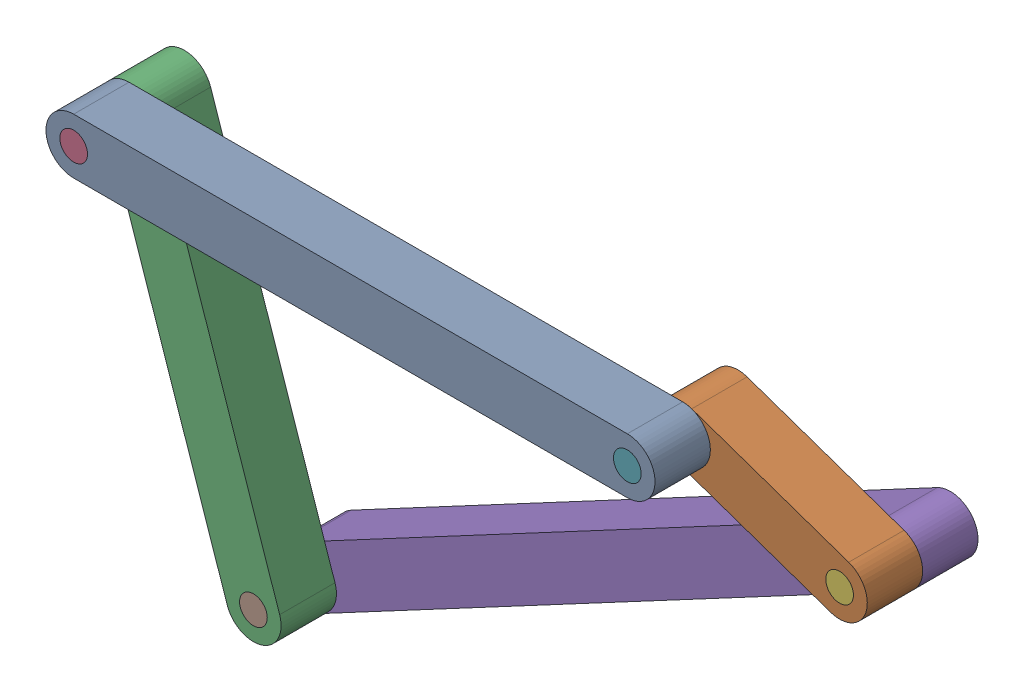
SolidWorks assembly 4 bar mech, configuration Default. Lengths in mm.
Overall size (141.45 79.42 30).
8 component instances, 5 part files, 21 mates.
Components (placement in the parent):
- 10-2: 10 [Default] at (20.648 20.834 -4.1693) size (110 10 10)
- 3-2: 3 [Default] at (84.8211 15.9225 -14.1693) x (-0.944872 0.327439 0) z (0 0 1) size (40 10 10)
- 7-2: 7 [Default] at (-18.1192 -12.3145 -14.1693) x (0.320937 -0.947101 0) z (0 0 1) size (80 10 10)
- Pin-2: Pin [Default] at (-29.352 20.834 -14.1693) x (-0.994228 -0.107291 0) z (0 0 1) size (5 5 20)
- 12-3: 12 [Default] at (46.0539 -17.2261 -24.1693) x (0.882338 0.470616 0) z (0 0 1) size (130 10 10)
- Pin-3: Pin [Default] at (98.9942 11.0109 -24.1693) size (5 5 20)
- Pin-4: Pin [Default] at (70.648 20.834 -14.1693) size (5 5 20)
- Pin-5: Pin [Default] at (-6.8864 -45.463 -24.1693) size (5 5 20)
Mates (geometry in assembly coordinates):
- Concentric3: concentric aligned: cylinder of 10-2 through (70.648 20.834 5.8307) axis (0 0 -1) radius 2.5; cylinder of 3-2 through (70.648 20.834 -4.1693) axis (0 0 -1) radius 2.5
- Coincident4: coincident anti-aligned: plane of 10-2 through (-29.352 20.834 -4.1693) normal (0 0 -1); plane of 3-2 through (98.9942 11.0109 -4.1693) normal (0 0 1)
- Coincident5: coincident anti-aligned: plane of 10-2 through (-29.352 20.834 -4.1693) normal (0 0 -1); plane of 7-2 through (-29.352 20.834 -4.1693) normal (0 0 1)
- Concentric5: concentric aligned: cylinder of 10-2 through (-29.352 20.834 5.8307) axis (0 0 -1) radius 2.5; cylinder of 7-2 through (-29.352 20.834 -4.1693) axis (0 0 -1) radius 2.5
- Concentric8: concentric aligned: cylinder of 10-2 through (-29.352 20.834 5.8307) axis (0 0 -1) radius 2.5; cylinder of Pin-2 through (-29.352 20.834 5.8307) axis (0 0 -1) radius 2.5
- Coincident9: coincident aligned: plane of 7-2 through (-29.352 20.834 -14.1693) normal (0 0 -1); plane of Pin-2 through (-29.352 20.834 -14.1693) normal (0 0 -1)
- Coincident10: coincident anti-aligned: plane of 7-2 through (-29.352 20.834 -14.1693) normal (0 0 -1); plane of 12-3 through (-6.8864 -45.463 -14.1693) normal (0 0 1)
- Coincident11: coincident anti-aligned: plane of 3-2 through (98.9942 11.0109 -14.1693) normal (0 0 -1); plane of 12-3 through (-6.8864 -45.463 -14.1693) normal (0 0 1)
- Concentric9: concentric aligned: cylinder of 3-2 through (98.9942 11.0109 -4.1693) axis (0 0 -1) radius 2.5; cylinder of 12-3 through (98.9942 11.0109 -14.1693) axis (0 0 -1) radius 2.5
- Coincident12: coincident anti-aligned: plane of 7-2 through (-29.352 20.834 -14.1693) normal (0 0 -1); plane of 12-3 through (-6.8864 -45.463 -14.1693) normal (0 0 1)
- Coincident13: coincident anti-aligned: circle of 7-2; circle of 12-3
- Concentric10: concentric aligned: cylinder of 12-3 through (98.9942 11.0109 -14.1693) axis (0 0 -1) radius 2.5; cylinder of Pin-3 through (98.9942 11.0109 -4.1693) axis (0 0 -1) radius 2.5
- Coincident14: coincident aligned: plane of 3-2 through (98.9942 11.0109 -4.1693) normal (0 0 1); plane of Pin-3 through (98.9942 11.0109 -4.1693) normal (0 0 1)
- Concentric11: concentric: cylinder of 10-2 through (70.648 20.834 5.8307) axis (0 0 -1) radius 2.5; cylinder of Pin-4 through (70.648 20.834 5.8307) axis (0 0 -1) radius 2.5
- Coincident15: coincident: plane of 10-2 through (-29.352 20.834 5.8307) normal (0 0 1); plane of Pin-4 through (70.648 20.834 5.8307) normal (0 0 1)
- Concentric12: concentric aligned: cylinder of 12-3 through (-6.8864 -45.463 -14.1693) axis (0 0 -1) radius 2.5; cylinder of Pin-5 through (-6.8864 -45.463 -4.1693) axis (0 0 -1) radius 2.5
- Coincident16: coincident aligned: plane of 12-3 through (-6.8864 -45.463 -24.1693) normal (0 0 -1); plane of Pin-5 through (-6.8864 -45.463 -24.1693) normal (0 0 -1)
- Coincident17: coincident aligned: plane of 12-3 through (-6.8864 -45.463 -24.1693) normal (0 0 -1); plane of Pin-3 through (98.9942 11.0109 -24.1693) normal (0 0 -1)
- Coincident18: coincident aligned: plane of 12-3 through (-6.8864 -45.463 -24.1693) normal (0 0 -1); plane of Pin-5 through (-6.8864 -45.463 -24.1693) normal (0 0 -1)
- Coincident19: coincident aligned: plane of 7-2 through (-29.352 20.834 -14.1693) normal (0 0 -1); plane of Pin-2 through (-29.352 20.834 -14.1693) normal (0 0 -1)
- Parallel1: parallel aligned: plane of 10-2 through (-29.352 20.834 -4.1693) normal (0 0 -1); plane of Pin-4 through (70.648 20.834 -14.1693) normal (0 0 -1)
